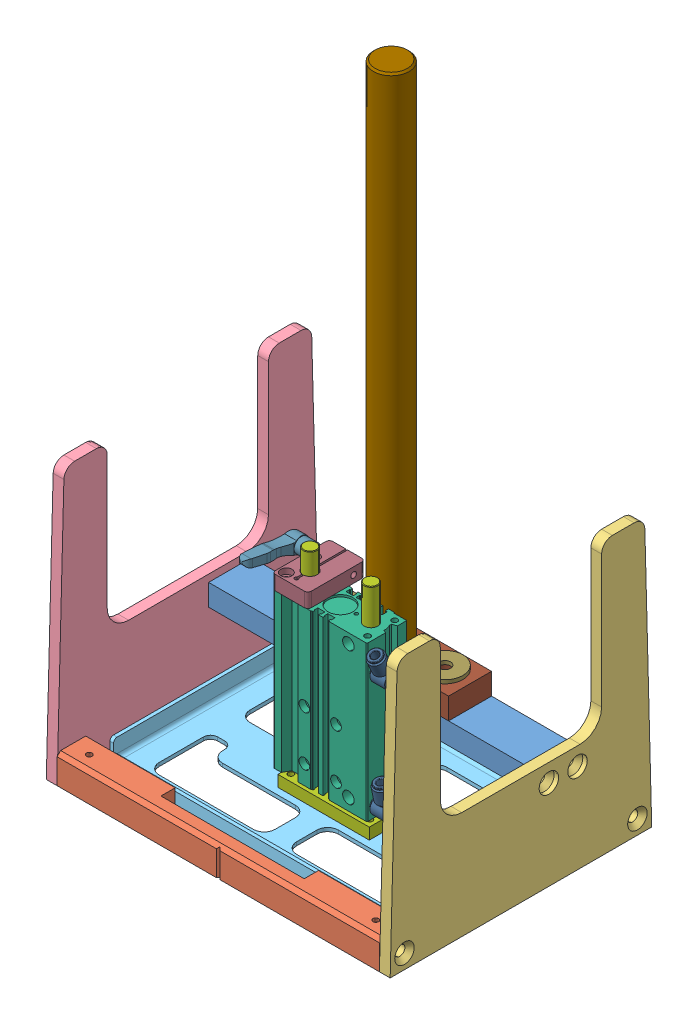
SolidWorks assembly R&D5959-11-001, configuration Default. Lengths in mm.
Overall size (304.8 552.45 231.84).
18 component instances, 14 part files, 39 mates.
Components (placement in the parent):
- R&D5959-11-104-H-1: R&D5959-11-104-H [Default] at origin size (285.75 19.05 38.1)
- R&D5959-11-105-H-1: R&D5959-11-105-H [Default] at (0 -66.675 140.6779) size (285.75 25.4 25.4)
- R&D5959-11-105-H-2: R&D5959-11-105-H [Default] at (0 -66.675 -65.7606) x (-1 0 0) z (0 0 -1) size (285.75 25.4 25.4)
- R&D5959-11-106-H-1: R&D5959-11-106-H [5086-21-107] at (142.875 -31.75 37.4587) x (0 1 0) z (1 0 0) size (241.3 231.84 9.53)
- R&D5959-11-106-3-H-1: R&D5959-11-106-3-H [5086-21-107] at (-142.875 -31.75 37.4587) x (0 1 0) z (-1 0 0) size (241.3 231.84 9.53)
- R&D5959-11-107-1: R&D5959-11-107 [Default] at (0 -76.2 37.4587) x (-1 0 0) z (0 0 -1) size (275.34 19.05 173.84)
- R&D5321-31 SMC MGPM20N-100-1: R&D5321-31 SMC MGPM20N-100 [MGPM20N-100] at (0 8.3 44.9875) x (1 0 0) z (0 -1 0) size (83 36 184.5)
  - R&D5321-31 SMC MGPM20N-100_MGPTube-1: R&D5321-31 SMC MGPM20N-100_MGPTube [20M] at origin size (83 36 137)
  - R&D5321-31 SMC MGPM20N-100_MGPRod-1: R&D5321-31 SMC MGPM20N-100_MGPRod [20M] at (0 0 -52.5) size (81 30 184.5)
- R&D5086-21-108-H-1: R&D5086-21-108-H [Default] at (0 -9.525 26.9875) x (0 0 -1) z (1 0 0) size (50.8 50.8 76.2)
- R&D5959-11-109-H-1: R&D5959-11-109-H [Default] at (0 244.475 0) x (1 0 0) z (0 -1 0) size (31.75 31.75 457.2)
- R&DAS2211FG-N01-07S-1: R&DAS2211FG-N01-07S [Default] at (51.0375 52.3 55.4875) x (0 -0.90635 -0.422527) z (0 -0.422527 0.90635) size (31 36.1 14.2)
- R&DAS2211FG-N01-07S-2: R&DAS2211FG-N01-07S [Default] at (51.0375 -49.7 55.4875) x (0 -0.979591 -0.201) z (0 -0.201 0.979591) size (31 36.1 14.2)
- R&D5959-11-110-H-1: R&D5959-11-110-H [Default] at (0 19.05 0) x (0 0 -1) z (-1 0 0) size (38.1 19.05 139.7)
- R&D15D350A-1: R&D15D350A [Default] at (47.625 30.1625 0) x (-0.379258 0 0.925291) z (0.925291 0 0.379258) size (31.75 3.17 31.75)
- R&D15D350A-2: R&D15D350A [Default] at (-47.625 30.1625 0) x (-0.379258 0 0.925291) z (0.925291 0 0.379258) size (31.75 3.17 31.75)
- R&D5634-15-108-1: R&D5634-15-108 [Default] at (-26.475 83.15 37.9375) x (-1 0 0) z (0 0 -1) size (31.75 12.7 50.8)
- R&D06451-1062-1: R&D06451-1062 [Default] at (-42.35 83.15 22.7625) x (0 0 1) z (0 -1 0) size (46.51 30.96 14.49)
Mates (geometry in assembly coordinates):
- Coincident1: coincident: plane of R&D5959-11-104-H-1 through (142.875 9.525 19.05) normal (1 0 0); plane of R&D5959-11-106-H-1 through (142.875 -79.375 -78.4606) normal (-1 0 0)
- Concentric1: concentric: cylinder of R&D5959-11-104-H-1 through (142.875 0 12.7) axis (1 0 0) radius 3.4; cylinder of R&D5959-11-106-H-1 through (152.4 0 12.7) axis (1 0 0) radius 4.5
- Concentric2: concentric: cylinder of R&D5959-11-104-H-1 through (142.875 0 -12.7) axis (1 0 0) radius 3.4; cylinder of R&D5959-11-106-H-1 through (152.4 0 -12.7) axis (1 0 0) radius 4.5
- Coincident2: coincident: plane of R&D5959-11-106-H-1 through (142.875 -79.375 -78.4606) normal (-1 0 0); plane of R&D5959-11-105-H-1 through (142.875 -79.375 153.3779) normal (1 0 0)
- Coincident22: coincident: plane of R&D5959-11-105-H-2 through (142.875 -79.375 -78.4606) normal (1 0 0); plane of R&D5959-11-106-H-1 through (142.875 -79.375 -78.4606) normal (-1 0 0)
- Coincident23: coincident: plane of R&D5959-11-106-H-1 through (152.4 -79.375 153.3779) normal (0 -1 0); plane of R&D5959-11-105-H-2 through (-142.875 -79.375 -78.4606) normal (0 -1 0)
- Coincident24: coincident: plane of R&D5959-11-105-H-1 through (-142.875 -79.375 153.3779) normal (-1 0 0); plane of R&D5959-11-106-3-H-1 through (-142.875 -79.375 -78.4606) normal (1 0 0)
- Concentric29: concentric: cylinder of R&D5959-11-105-H-1 through (-142.875 -66.675 140.6779) axis (-1 0 0) radius 3.4; cylinder of R&D5959-11-106-3-H-1 through (-152.4 -66.675 140.6779) axis (-1 0 0) radius 4.5
- Concentric30: concentric: cylinder of R&D5959-11-105-H-2 through (-142.875 -66.675 -65.7606) axis (-1 0 0) radius 3.4; cylinder of R&D5959-11-106-3-H-1 through (-152.4 -66.675 -65.7606) axis (-1 0 0) radius 4.5
- Concentric60: concentric: cylinder of R&D5959-11-105-H-1 through (142.875 -66.675 140.6779) axis (1 0 0) radius 3.4; cylinder of R&D5959-11-106-H-1 through (152.4 -66.675 140.6779) axis (1 0 0) radius 4.5
- Coincident72: coincident: plane of R&D5959-11-104-H-1 through (142.875 -9.525 19.05) normal (0 -1 0); plane of R&D5086-21-108-H-1 through (38.1 -9.525 26.9875) normal (0 1 0)
- Coincident75: coincident: plane of R&D5959-11-107-1 through (131.318 -76.2 -43.1101) normal (0 1 0); plane of R&D5321-31 SMC MGPM20N-100-1/R&D5321-31 SMC MGPM20N-100_MGPRod-1 through (-40.5 -76.2 29.9875) normal (0 -1 0)
- Coincident77: coincident: plane of R&D5959-11-105-H-2 through (-142.875 -79.375 -78.4606) normal (0 -1 0); plane of R&D5959-11-107-1 through (131.318 -79.375 -43.1101) normal (0 -1 0)
- Coincident78: coincident: plane of R&D5321-31 SMC MGPM20N-100-1/R&D5321-31 SMC MGPM20N-100_MGPTube-1 through (0 8.3 44.9875) normal (1 0 0); plane of R&D5086-21-108-H-1 through (0 -9.525 26.9875) normal (1 0 0)
- Coincident79: coincident: plane of R&D5321-31 SMC MGPM20N-100-1/R&D5321-31 SMC MGPM20N-100_MGPTube-1 through (-41.5 -150.671 26.9875) normal (0 0 -1); plane of R&D5086-21-108-H-1 through (38.1 -9.525 26.9875) normal (0 0 1)
- Coincident80: coincident: plane of R&DAS2211FG-N01-07S-1 through (36.7375 54.6304 61.8882) normal (-1 0 0); plane of R&DAS2211FG-N01-07S-2 through (36.7375 -45.9498 61.1739) normal (-1 0 0)
- Distance1: distance = 4.7625 mm: plane of R&D5321-31 SMC MGPM20N-100-1/R&D5321-31 SMC MGPM20N-100_MGPTube-1 through (41.5 -150.671 62.9875) normal (1 0 0); plane of R&DAS2211FG-N01-07S-2 through (36.7375 -45.9498 61.1739) normal (-1 0 0)
- Concentric65: concentric: circle of R&D5321-31 SMC MGPM20N-100-1/R&D5321-31 SMC MGPM20N-100_MGPTube-1; cylinder of R&DAS2211FG-N01-07S-1 through (56.7375 52.3 55.4875) axis (-1 0 0) radius 7.1
- Concentric66: concentric: circle of R&D5321-31 SMC MGPM20N-100-1/R&D5321-31 SMC MGPM20N-100_MGPTube-1; circle of R&DAS2211FG-N01-07S-2
- Coincident87: coincident: plane of R&D5959-11-104-H-1 through (0 0 0) normal (0 0 1); plane of R&D5959-11-109-H-1 through (0 244.475 0) normal (0 0 1)
- Distance2: distance = 6.35 mm: plane of R&D5959-11-104-H-1 through (142.875 9.525 19.05) normal (0 1 0); plane of R&D5959-11-109-H-1 through (0 15.875 0) normal (0 -1 0)
- Coincident89: coincident: plane of R&D5959-11-104-H-1 through (0 0 0) normal (1 0 0); plane of R&D5959-11-109-H-1 through (0 244.475 0) normal (1 0 0)
- Coincident90: coincident: plane of R&D5959-11-104-H-1 through (142.875 9.525 19.05) normal (0 1 0); plane of R&D5959-11-110-H-1 through (-69.85 9.525 19.05) normal (0 -1 0)
- Coincident91: coincident: plane of R&D5959-11-104-H-1 through (0 0 0) normal (0 0 1); plane of R&D5959-11-110-H-1 through (0 19.05 0) normal (0 0 -1)
- Coincident92: coincident: plane of R&D5959-11-104-H-1 through (0 0 0) normal (1 0 0); plane of R&D5959-11-110-H-1 through (0 19.05 0) normal (-1 0 0)
- Coincident93: coincident: plane of R&D15D350A-1 through (47.625 28.575 0) normal (0 -1 0); plane of R&D15D350A-2 through (-47.625 28.575 0) normal (0 -1 0)
- Coincident94: coincident: plane of R&D5959-11-110-H-1 through (-69.85 28.575 19.05) normal (0 1 0); plane of R&D15D350A-1 through (47.625 28.575 0) normal (0 -1 0)
- Concentric67: concentric: cylinder of R&D5959-11-110-H-1 through (47.625 28.576 0) axis (0 -1 0) radius 9.525; cylinder of R&D15D350A-1 through (47.625 28.575 0) axis (0 1 0) radius 4.9609
- Concentric68: concentric: cylinder of R&D5959-11-110-H-1 through (-47.625 28.576 0) axis (0 -1 0) radius 9.525; cylinder of R&D15D350A-2 through (-47.625 28.575 0) axis (0 1 0) radius 4.9609
- Concentric69: concentric: cylinder of R&D5959-11-104-H-1 through (-19.05 -9.525 -12.7) axis (0 -1 0) radius 2.1; cylinder of R&D5086-21-108-H-1 through (-19.05 -9.525 -12.7) axis (0 1 0) radius 2.7781
- Concentric70: concentric: cylinder of R&D5959-11-104-H-1 through (19.05 -9.525 12.7) axis (0 -1 0) radius 2.1; cylinder of R&D5086-21-108-H-1 through (19.05 -9.525 12.7) axis (0 1 0) radius 2.7781
- Width1: width: plane of R&D5959-11-107-1 through (124.968 -60.325 -49.4601) normal (0 0 -1); plane of R&D5959-11-107-1 through (0 -76.2 124.3774) normal (0 0 1); plane of R&D5959-11-105-H-2 through (-142.875 -53.975 -53.0606) normal (0 0 1); plane of R&D5959-11-105-H-1 through (142.875 -53.975 127.9779) normal (0 0 -1)
- Width2: width: plane of R&D5959-11-107-1 through (-137.668 -76.2 111.6774) normal (-1 0 0); plane of R&D5959-11-107-1 through (137.668 -76.2 -36.7601) normal (1 0 0); plane of R&D5959-11-106-H-1 through (152.4 -79.375 -78.4606) normal (1 0 0); plane of R&D5959-11-106-3-H-1 through (-152.4 -79.375 -78.4606) normal (-1 0 0)
- Concentric71: concentric: cylinder of R&D5321-31 SMC MGPM20N-100-1/R&D5321-31 SMC MGPM20N-100_MGPRod-1 through (-27 125.2706 44.9875) axis (0 -1 0) radius 6; cylinder of R&D5634-15-108-1 through (-27 76.799 44.9875) axis (0 1 0) radius 6
- Concentric72: concentric: cylinder of R&D5321-31 SMC MGPM20N-100-1/R&D5321-31 SMC MGPM20N-100_MGPTube-1 through (-36 63.8 56.9875) axis (0 1 0) radius 2.5; cylinder of R&D5634-15-108-1 through (-36 89.5 56.9875) axis (0 1 0) radius 5
- Coincident95: coincident: plane of R&D5321-31 SMC MGPM20N-100-1/R&D5321-31 SMC MGPM20N-100_MGPTube-1 through (0 76.8 44.9875) normal (0 1 0); plane of R&D5634-15-108-1 through (-10.6 76.8 12.5375) normal (0 -1 0)
- Coincident96: coincident: plane of R&D5634-15-108-1 through (-42.35 76.8 12.5375) normal (-1 0 0); plane of R&D06451-1062-1 through (-42.35 83.15 27.4625) normal (1 0 0)
- Concentric73: concentric: cylinder of R&D5634-15-108-1 through (-42.35 83.15 22.7625) axis (-1 0 0) radius 3.3735; cylinder of R&D06451-1062-1 through (-42.35 83.15 22.7625) axis (-1 0 0) radius 5
- Parallel1: parallel: plane of R&D5634-15-108-1 through (-10.6 89.5 12.5375) normal (0 1 0); plane of R&D06451-1062-1 through (-42.35 83.15 22.7625) normal (0 -1 0)
